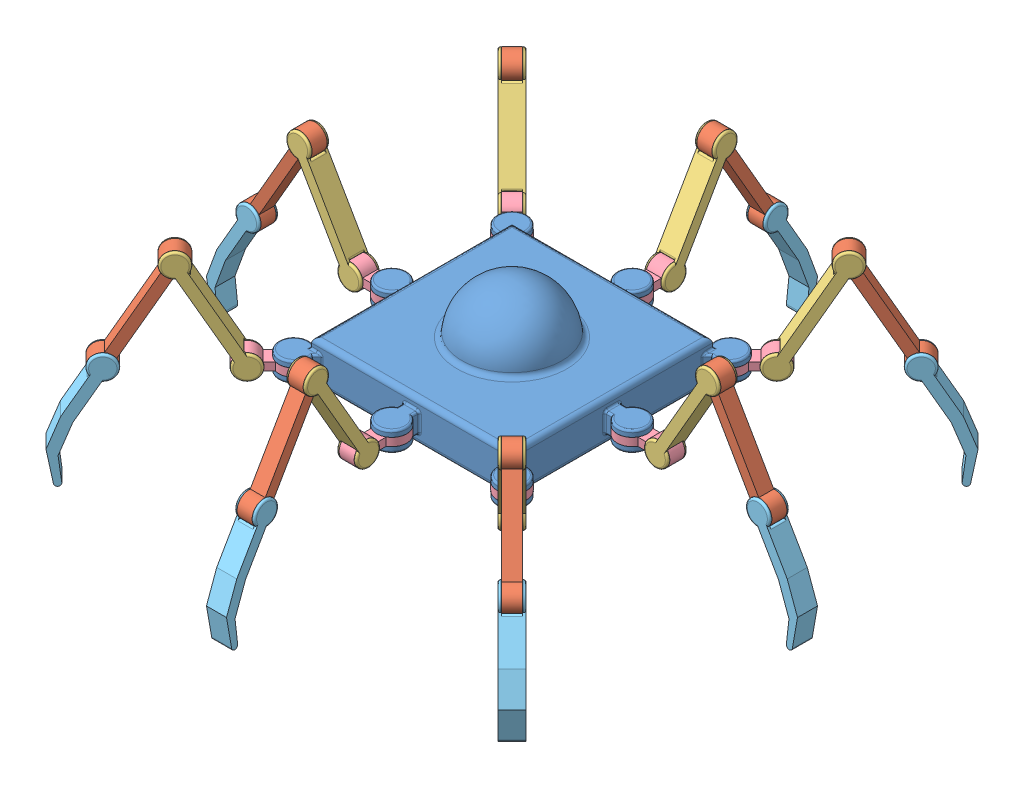
SolidWorks assembly SpiderBot_3Legs, configuration Default. Lengths in mm.
Overall size (634.89 234.57 634.89).
33 component instances, 5 part files, 146 mates.
Components (placement in the parent):
- spider_body-1: spider_body [Default] at (0 150 0) x (0 0 -1) z (0 -1 0) size (270 270 90)
- Link_C-24: Link_C [Default] at (-183.9152 176.5882 -194.5218) x (0.353553 0.866025 0.353553) z (-0.707107 0 0.707107) size (125.82 24 15)
- Link_B-24: Link_B [Default] at (-140.0258 176.5882 -154.1679) x (-0.707107 0 0.707107) z (-0.353553 0.866025 -0.353553) size (20.32 24 125.82)
- Link_A-24: Link_A [Default] at (-108.832 134 -108.832) x (-0.707107 0 -0.707107) z (0 -1 0) size (59.99 30 24)
- Link_D-24: Link_D [Default] at (-232.2874 88.4118 -218.1453) x (0.707107 0 -0.707107) z (0.353553 0.866025 0.353553) size (20.32 36.78 116.49)
- Link_C-26: Link_C [Default] at (-194.5218 176.5882 183.9152) x (0.353553 0.866025 -0.353553) z (0.707107 0 0.707107) size (125.82 24 15)
- Link_B-26: Link_B [Default] at (-154.1679 176.5882 140.0258) x (0.707107 0 0.707107) z (-0.353553 0.866025 0.353553) size (20.32 24 125.82)
- Link_A-26: Link_A [Default] at (-108.832 134 108.832) x (-0.707107 0 0.707107) z (0 -1 0) size (59.99 30 24)
- Link_D-26: Link_D [Default] at (-218.1453 88.4118 232.2874) x (-0.707107 0 -0.707107) z (0.353553 0.866025 -0.353553) size (20.32 36.78 116.49)
- Link_C-27: Link_C [Default] at (183.9152 176.5882 194.5218) x (-0.353553 0.866025 -0.353553) z (0.707107 0 -0.707107) size (125.82 24 15)
- Link_B-27: Link_B [Default] at (140.0258 176.5882 154.1679) x (0.707107 0 -0.707107) z (0.353553 0.866025 0.353553) size (20.32 24 125.82)
- Link_A-27: Link_A [Default] at (108.832 134 108.832) x (0.707107 0 0.707107) z (0 -1 0) size (59.99 30 24)
- Link_D-27: Link_D [Default] at (232.2874 88.4118 218.1453) x (-0.707107 0 0.707107) z (-0.353553 0.866025 -0.353553) size (20.32 36.78 116.49)
- Link_B-33: Link_B [Default] at (154.1679 176.5882 -140.0258) x (-0.707107 0 -0.707107) z (0.353553 0.866025 -0.353553) size (20.32 24 125.82)
- Link_D-31: Link_D [Default] at (218.1453 88.4118 -232.2874) x (0.707107 0 0.707107) z (-0.353553 0.866025 0.353553) size (20.32 36.78 116.49)
- Link_A-31: Link_A [Default] at (108.832 134 -108.832) x (0.707107 0 -0.707107) z (0 -1 0) size (59.99 30 24)
- Link_C-31: Link_C [Default] at (194.5218 176.5882 -183.9152) x (-0.353553 0.866025 0.353553) z (-0.707107 0 -0.707107) size (125.82 24 15)
- Link_D-34: Link_D [Default] at (-284.5923 88.4118 10) x (0 0 -1) z (0.5 0.866025 0) size (20.32 36.78 116.49)
- Link_A-34: Link_A [Default] at (-120 134 0) x (-1 0 0) z (0 -1 0) size (59.99 30 24)
- Link_B-36: Link_B [Default] at (-174.1146 176.5882 -10) x (0 0 1) z (-0.5 0.866025 0) size (20.32 24 125.82)
- Link_C-34: Link_C [Default] at (-233.6836 176.5882 -7.5) x (0.5 0.866025 0) z (0 0 1) size (125.82 24 15)
- Link_A-35: Link_A [Default] at (120 134 0) x (1 0 0) z (0 -1 0) size (59.99 30 24)
- Link_D-35: Link_D [Default] at (284.5923 88.4118 -10) x (0 0 1) z (-0.5 0.866025 0) size (20.32 36.78 116.49)
- Link_C-35: Link_C [Default] at (233.6836 176.5882 7.5) x (-0.5 0.866025 0) z (0 0 -1) size (125.82 24 15)
- Link_B-37: Link_B [Default] at (174.1146 176.5882 10) x (0 0 -1) z (0.5 0.866025 0) size (20.32 24 125.82)
- Link_A-36: Link_A [Default] at (0 134 120) x (0 0 1) z (0 -1 0) size (59.99 30 24)
- Link_D-36: Link_D [Default] at (10 88.4118 284.5923) x (-1 0 0) z (0 0.866025 -0.5) size (20.32 36.78 116.49)
- Link_C-36: Link_C [Default] at (-7.5 176.5882 233.6836) x (0 0.866025 -0.5) z (1 0 0) size (125.82 24 15)
- Link_B-38: Link_B [Default] at (-10 176.5882 174.1146) x (1 0 0) z (0 0.866025 0.5) size (20.32 24 125.82)
- Link_A-37: Link_A [Default] at (0 134 -120) x (0 0 -1) z (0 -1 0) size (59.99 30 24)
- Link_D-37: Link_D [Default] at (-10 88.4118 -284.5923) x (1 0 0) z (0 0.866025 0.5) size (20.32 36.78 116.49)
- Link_C-37: Link_C [Default] at (7.5 176.5882 -233.6836) x (0 0.866025 0.5) z (-1 0 0) size (125.82 24 15)
- Link_B-39: Link_B [Default] at (10 176.5882 -174.1146) x (-1 0 0) z (0 0.866025 -0.5) size (20.32 24 125.82)
Mates (geometry in assembly coordinates):
- Coincident4: coincident anti-aligned: plane of Link_B-2 through (235.0341 -365.5738 720.8033) normal (-1 0 0); plane of Link_C-2 through (235.0341 -453.7502 771.712) normal (1 0 0)
- Concentric4: concentric anti-aligned: cylinder of Link_B-2 through (220.0341 -365.5738 720.8033) axis (1 0 0) radius 4; cylinder of Link_C-2 through (235.0341 -365.5738 720.8033) axis (-1 0 0) radius 4
- Coincident5: coincident anti-aligned: plane of Link_C-2 through (235.0341 -453.7502 771.712) normal (1 0 0); plane of Link_D-2 through (235.0341 -453.7502 771.712) normal (-1 0 0)
- Concentric6: concentric aligned: cylinder of Link_C-2 through (235.0341 -453.7502 771.712) axis (-1 0 0) radius 4; cylinder of Link_D-2 through (235.0341 -453.7502 771.712) axis (-1 0 0) radius 4
- Coincident7: coincident anti-aligned: plane of Link_B-3 through (281.248 -759.0313 934.2797) normal (-1 0 0); plane of Link_C-3 through (281.248 -847.2078 985.1885) normal (1 0 0)
- Concentric7: concentric anti-aligned: cylinder of Link_B-3 through (266.248 -759.0313 934.2797) axis (1 0 0) radius 4; cylinder of Link_C-3 through (281.248 -759.0313 934.2797) axis (-1 0 0) radius 4
- Coincident8: coincident anti-aligned: plane of Link_C-3 through (281.248 -847.2078 985.1885) normal (1 0 0); plane of Link_D-3 through (281.248 -847.2078 985.1885) normal (-1 0 0)
- Concentric9: concentric aligned: cylinder of Link_C-3 through (281.248 -847.2078 985.1885) axis (-1 0 0) radius 4; cylinder of Link_D-3 through (281.248 -847.2078 985.1885) axis (-1 0 0) radius 4
- Coincident10: coincident anti-aligned: plane of Link_B-4 through (178.5336 -465.5708 822.703) normal (-1 0 0); plane of Link_C-4 through (178.5336 -553.7473 873.6117) normal (1 0 0)
- Concentric10: concentric anti-aligned: cylinder of Link_B-4 through (163.5336 -465.5708 822.703) axis (1 0 0) radius 4; cylinder of Link_C-4 through (178.5336 -465.5708 822.703) axis (-1 0 0) radius 4
- Coincident11: coincident anti-aligned: plane of Link_C-4 through (178.5336 -553.7473 873.6117) normal (1 0 0); plane of Link_D-4 through (178.5336 -553.7473 873.6117) normal (-1 0 0)
- Concentric12: concentric aligned: cylinder of Link_C-4 through (178.5336 -553.7473 873.6117) axis (-1 0 0) radius 4; cylinder of Link_D-4 through (178.5336 -553.7473 873.6117) axis (-1 0 0) radius 4
- Coincident13: coincident anti-aligned: plane of Link_B-5 through (262.376 -1013.0932 1106.1332) normal (-1 0 0); plane of Link_C-5 through (262.376 -1101.2696 1157.0419) normal (1 0 0)
- Concentric13: concentric anti-aligned: cylinder of Link_B-5 through (247.376 -1013.0932 1106.1332) axis (1 0 0) radius 4; cylinder of Link_C-5 through (262.376 -1013.0932 1106.1332) axis (-1 0 0) radius 4
- Coincident14: coincident anti-aligned: plane of Link_C-5 through (262.376 -1101.2696 1157.0419) normal (1 0 0); plane of Link_D-5 through (262.376 -1101.2696 1157.0419) normal (-1 0 0)
- Concentric15: concentric aligned: cylinder of Link_C-5 through (262.376 -1101.2696 1157.0419) axis (-1 0 0) radius 4; cylinder of Link_D-5 through (262.376 -1101.2696 1157.0419) axis (-1 0 0) radius 4
- Coincident16: coincident anti-aligned: plane of Link_B-6 through (534.9738 -1642.7072 1309.0583) normal (-1 0 0); plane of Link_C-6 through (534.9738 -1730.8837 1359.9671) normal (1 0 0)
- Concentric16: concentric anti-aligned: cylinder of Link_B-6 through (519.9738 -1642.7072 1309.0583) axis (1 0 0) radius 4; cylinder of Link_C-6 through (534.9738 -1642.7072 1309.0583) axis (-1 0 0) radius 4
- Coincident17: coincident anti-aligned: plane of Link_C-6 through (534.9738 -1730.8837 1359.9671) normal (1 0 0); plane of Link_D-6 through (534.9738 -1730.8837 1359.9671) normal (-1 0 0)
- Concentric18: concentric aligned: cylinder of Link_C-6 through (534.9738 -1730.8837 1359.9671) axis (-1 0 0) radius 4; cylinder of Link_D-6 through (534.9738 -1730.8837 1359.9671) axis (-1 0 0) radius 4
- Coincident19: coincident anti-aligned: plane of Link_B-7 through (-306.3909 -269.9837 1039.0888) normal (-1 0 0); plane of Link_C-7 through (-306.3909 -358.1602 1089.9975) normal (1 0 0)
- Concentric19: concentric anti-aligned: cylinder of Link_B-7 through (-321.3909 -269.9837 1039.0888) axis (1 0 0) radius 4; cylinder of Link_C-7 through (-306.3909 -269.9837 1039.0888) axis (-1 0 0) radius 4
- Coincident20: coincident anti-aligned: plane of Link_C-7 through (-306.3909 -358.1602 1089.9975) normal (1 0 0); plane of Link_D-7 through (-306.3909 -358.1602 1089.9975) normal (-1 0 0)
- Concentric21: concentric aligned: cylinder of Link_C-7 through (-306.3909 -358.1602 1089.9975) axis (-1 0 0) radius 4; cylinder of Link_D-7 through (-306.3909 -358.1602 1089.9975) axis (-1 0 0) radius 4
- Coincident22: coincident anti-aligned: plane of Link_B-8 through (-311.8852 -488.0983 1179.1514) normal (-1 0 0); plane of Link_C-8 through (-311.8852 -576.2747 1230.0601) normal (1 0 0)
- Concentric22: concentric anti-aligned: cylinder of Link_B-8 through (-326.8852 -488.0983 1179.1514) axis (1 0 0) radius 4; cylinder of Link_C-8 through (-311.8852 -488.0983 1179.1514) axis (-1 0 0) radius 4
- Coincident23: coincident anti-aligned: plane of Link_C-8 through (-311.8852 -576.2747 1230.0601) normal (1 0 0); plane of Link_D-8 through (-311.8852 -576.2747 1230.0601) normal (-1 0 0)
- Concentric24: concentric aligned: cylinder of Link_C-8 through (-311.8852 -576.2747 1230.0601) axis (-1 0 0) radius 4; cylinder of Link_D-8 through (-311.8852 -576.2747 1230.0601) axis (-1 0 0) radius 4
- Coincident25: coincident anti-aligned: plane of Link_B-9 through (-611.4857 -390.9688 1327.6493) normal (-1 0 0); plane of Link_C-9 through (-611.4857 -479.1453 1378.558) normal (1 0 0)
- Concentric25: concentric anti-aligned: cylinder of Link_B-9 through (-626.4857 -390.9688 1327.6493) axis (1 0 0) radius 4; cylinder of Link_C-9 through (-611.4857 -390.9688 1327.6493) axis (-1 0 0) radius 4
- Coincident26: coincident anti-aligned: plane of Link_C-9 through (-611.4857 -479.1453 1378.558) normal (1 0 0); plane of Link_D-9 through (-611.4857 -479.1453 1378.558) normal (-1 0 0)
- Concentric27: concentric aligned: cylinder of Link_C-9 through (-611.4857 -479.1453 1378.558) axis (-1 0 0) radius 4; cylinder of Link_D-9 through (-611.4857 -479.1453 1378.558) axis (-1 0 0) radius 4
- Coincident28: coincident anti-aligned: plane of Link_B-10 through (-139.42 -657.5126 1164.5577) normal (-1 0 0); plane of Link_C-10 through (-139.42 -745.689 1215.4664) normal (1 0 0)
- Concentric28: concentric anti-aligned: cylinder of Link_B-10 through (-154.42 -657.5126 1164.5577) axis (1 0 0) radius 4; cylinder of Link_C-10 through (-139.42 -657.5126 1164.5577) axis (-1 0 0) radius 4
- Coincident29: coincident anti-aligned: plane of Link_C-10 through (-139.42 -745.689 1215.4664) normal (1 0 0); plane of Link_D-10 through (-139.42 -745.689 1215.4664) normal (-1 0 0)
- Concentric30: concentric aligned: cylinder of Link_C-10 through (-139.42 -745.689 1215.4664) axis (-1 0 0) radius 4; cylinder of Link_D-10 through (-139.42 -745.689 1215.4664) axis (-1 0 0) radius 4
- Coincident31: coincident anti-aligned: plane of Link_B-11 through (-139.42 -657.5126 1164.5577) normal (-1 0 0); plane of Link_C-11 through (-139.42 -745.689 1215.4664) normal (1 0 0)
- Concentric31: concentric anti-aligned: cylinder of Link_B-11 through (-154.42 -657.5126 1164.5577) axis (1 0 0) radius 4; cylinder of Link_C-11 through (-139.42 -657.5126 1164.5577) axis (-1 0 0) radius 4
- Coincident32: coincident anti-aligned: plane of Link_C-11 through (-139.42 -745.689 1215.4664) normal (1 0 0); plane of Link_D-11 through (-139.42 -745.689 1215.4664) normal (-1 0 0)
- Concentric33: concentric aligned: cylinder of Link_C-11 through (-139.42 -745.689 1215.4664) axis (-1 0 0) radius 4; cylinder of Link_D-11 through (-139.42 -745.689 1215.4664) axis (-1 0 0) radius 4
- Coincident34: coincident anti-aligned: plane of Link_B-12 through (-94.7509 -804.43 1225.1322) normal (-1 0 0); plane of Link_C-12 through (-94.7509 -892.6065 1276.0409) normal (1 0 0)
- Concentric34: concentric anti-aligned: cylinder of Link_B-12 through (-109.7509 -804.43 1225.1322) axis (1 0 0) radius 4; cylinder of Link_C-12 through (-94.7509 -804.43 1225.1322) axis (-1 0 0) radius 4
- Coincident35: coincident anti-aligned: plane of Link_C-12 through (-94.7509 -892.6065 1276.0409) normal (1 0 0); plane of Link_D-12 through (-94.7509 -892.6065 1276.0409) normal (-1 0 0)
- Concentric36: concentric aligned: cylinder of Link_C-12 through (-94.7509 -892.6065 1276.0409) axis (-1 0 0) radius 4; cylinder of Link_D-12 through (-94.7509 -892.6065 1276.0409) axis (-1 0 0) radius 4
- Concentric78: concentric anti-aligned: cylinder of Link_C-24 through (-173.461 218.1765 -162.8544) axis (0.707107 0 -0.707107) radius 4; cylinder of Link_B-24 through (-162.8544 218.1765 -173.461) axis (-0.707107 0 0.707107) radius 4
- Concentric79: concentric anti-aligned: cylinder of Link_B-24 through (-126.8565 130 -137.4631) axis (-0.707107 0 0.707107) radius 4; cylinder of Link_A-24 through (-142.7664 130 -121.5532) axis (0.707107 0 -0.707107) radius 5
- Coincident86: coincident anti-aligned: plane of Link_B-24 through (-137.4631 130 -126.8565) normal (0.707107 0 -0.707107); plane of Link_A-24 through (-123.3209 126 -112.7143) normal (-0.707107 0 0.707107)
- Coincident87: coincident anti-aligned: plane of Link_C-24 through (-198.8522 130 -209.4588) normal (0.707107 0 -0.707107); plane of Link_B-24 through (-162.8544 218.1765 -173.461) normal (-0.707107 0 0.707107)
- Coincident88: coincident anti-aligned: plane of Link_C-24 through (-209.4588 130 -198.8522) normal (-0.707107 0 0.707107); plane of Link_B-24 through (-173.461 218.1765 -162.8544) normal (0.707107 0 -0.707107)
- Coincident89: coincident anti-aligned: plane of Link_C-24 through (-198.8522 130 -209.4588) normal (0.707107 0 -0.707107); plane of Link_D-24 through (-198.8522 130 -209.4588) normal (-0.707107 0 0.707107)
- Concentric80: concentric aligned: cylinder of Link_C-24 through (-209.4588 130 -198.8522) axis (0.707107 0 -0.707107) radius 4; cylinder of Link_D-24 through (-209.4588 130 -198.8522) axis (0.707107 0 -0.707107) radius 4
- Coincident90: coincident anti-aligned: plane of Link_B-24 through (-126.8565 130 -137.4631) normal (-0.707107 0 0.707107); plane of Link_A-24 through (-112.7143 126 -123.3209) normal (0.707107 0 -0.707107)
- Coincident91: coincident anti-aligned: plane of Link_C-24 through (-209.4588 130 -198.8522) normal (-0.707107 0 0.707107); plane of Link_D-24 through (-209.4588 130 -198.8522) normal (0.707107 0 -0.707107)
- Concentric84: concentric anti-aligned: cylinder of Link_C-26 through (-162.8544 218.1765 173.461) axis (-0.707107 0 -0.707107) radius 4; cylinder of Link_B-26 through (-173.461 218.1765 162.8544) axis (0.707107 0 0.707107) radius 4
- Concentric85: concentric anti-aligned: cylinder of Link_B-26 through (-137.4631 130 126.8565) axis (0.707107 0 0.707107) radius 4; cylinder of Link_A-26 through (-121.5532 130 142.7664) axis (-0.707107 0 -0.707107) radius 5
- Coincident98: coincident anti-aligned: plane of Link_B-26 through (-126.8565 130 137.4631) normal (-0.707107 0 -0.707107); plane of Link_A-26 through (-112.7143 126 123.3209) normal (0.707107 0 0.707107)
- Coincident99: coincident anti-aligned: plane of Link_C-26 through (-209.4588 130 198.8522) normal (-0.707107 0 -0.707107); plane of Link_B-26 through (-173.461 218.1765 162.8544) normal (0.707107 0 0.707107)
- Coincident100: coincident anti-aligned: plane of Link_C-26 through (-198.8522 130 209.4588) normal (0.707107 0 0.707107); plane of Link_B-26 through (-162.8544 218.1765 173.461) normal (-0.707107 0 -0.707107)
- Coincident101: coincident anti-aligned: plane of Link_C-26 through (-209.4588 130 198.8522) normal (-0.707107 0 -0.707107); plane of Link_D-26 through (-209.4588 130 198.8522) normal (0.707107 0 0.707107)
- Concentric86: concentric aligned: cylinder of Link_C-26 through (-198.8522 130 209.4588) axis (-0.707107 0 -0.707107) radius 4; cylinder of Link_D-26 through (-198.8522 130 209.4588) axis (-0.707107 0 -0.707107) radius 4
- Coincident102: coincident anti-aligned: plane of Link_B-26 through (-137.4631 130 126.8565) normal (0.707107 0 0.707107); plane of Link_A-26 through (-123.3209 126 112.7143) normal (-0.707107 0 -0.707107)
- Coincident103: coincident anti-aligned: plane of Link_C-26 through (-198.8522 130 209.4588) normal (0.707107 0 0.707107); plane of Link_D-26 through (-198.8522 130 209.4588) normal (-0.707107 0 -0.707107)
- Concentric87: concentric anti-aligned: cylinder of Link_C-27 through (173.461 218.1765 162.8544) axis (-0.707107 0 0.707107) radius 4; cylinder of Link_B-27 through (162.8544 218.1765 173.461) axis (0.707107 0 -0.707107) radius 4
- Concentric88: concentric anti-aligned: cylinder of Link_B-27 through (126.8565 130 137.4631) axis (0.707107 0 -0.707107) radius 4; cylinder of Link_A-27 through (142.7664 130 121.5532) axis (-0.707107 0 0.707107) radius 5
- Coincident104: coincident anti-aligned: plane of Link_B-27 through (137.4631 130 126.8565) normal (-0.707107 0 0.707107); plane of Link_A-27 through (123.3209 126 112.7143) normal (0.707107 0 -0.707107)
- Coincident105: coincident anti-aligned: plane of Link_C-27 through (198.8522 130 209.4588) normal (-0.707107 0 0.707107); plane of Link_B-27 through (162.8544 218.1765 173.461) normal (0.707107 0 -0.707107)
- Coincident106: coincident anti-aligned: plane of Link_C-27 through (209.4588 130 198.8522) normal (0.707107 0 -0.707107); plane of Link_B-27 through (173.461 218.1765 162.8544) normal (-0.707107 0 0.707107)
- Coincident107: coincident anti-aligned: plane of Link_C-27 through (198.8522 130 209.4588) normal (-0.707107 0 0.707107); plane of Link_D-27 through (198.8522 130 209.4588) normal (0.707107 0 -0.707107)
- Concentric89: concentric aligned: cylinder of Link_C-27 through (209.4588 130 198.8522) axis (-0.707107 0 0.707107) radius 4; cylinder of Link_D-27 through (209.4588 130 198.8522) axis (-0.707107 0 0.707107) radius 4
- Coincident108: coincident anti-aligned: plane of Link_B-27 through (126.8565 130 137.4631) normal (0.707107 0 -0.707107); plane of Link_A-27 through (112.7143 126 123.3209) normal (-0.707107 0 0.707107)
- Coincident109: coincident anti-aligned: plane of Link_C-27 through (209.4588 130 198.8522) normal (0.707107 0 -0.707107); plane of Link_D-27 through (209.4588 130 198.8522) normal (-0.707107 0 0.707107)
- Coincident124: coincident anti-aligned: plane of spider_body-1 through (108.832 134 108.832) normal (0 -1 0); plane of Link_A-27 through (108.832 134 108.832) normal (0 1 0)
- Coincident125: coincident anti-aligned: plane of spider_body-1 through (108.832 126 108.832) normal (0 1 0); plane of Link_A-27 through (108.832 126 108.832) normal (0 -1 0)
- Concentric97: concentric anti-aligned: cylinder of spider_body-1 through (108.832 134 108.832) axis (0 -1 0) radius 10; cylinder of Link_A-27 through (108.832 126 108.832) axis (0 1 0) radius 10
- Coincident126: coincident anti-aligned: plane of spider_body-1 through (-108.832 134 108.832) normal (0 -1 0); plane of Link_A-26 through (-108.832 134 108.832) normal (0 1 0)
- Coincident127: coincident anti-aligned: plane of spider_body-1 through (-108.832 126 108.832) normal (0 1 0); plane of Link_A-26 through (-108.832 126 108.832) normal (0 -1 0)
- Concentric98: concentric anti-aligned: cylinder of spider_body-1 through (-108.832 134 108.832) axis (0 -1 0) radius 10; cylinder of Link_A-26 through (-108.832 126 108.832) axis (0 1 0) radius 10
- Coincident138: coincident anti-aligned: plane of Link_B-33 through (162.8544 218.1765 -173.461) normal (0.707107 0 0.707107); plane of Link_C-31 through (198.8522 130 -209.4588) normal (-0.707107 0 -0.707107)
- Coincident139: coincident anti-aligned: plane of Link_D-31 through (209.4588 130 -198.8522) normal (-0.707107 0 -0.707107); plane of Link_C-31 through (209.4588 130 -198.8522) normal (0.707107 0 0.707107)
- Coincident140: coincident anti-aligned: plane of Link_D-31 through (198.8522 130 -209.4588) normal (0.707107 0 0.707107); plane of Link_C-31 through (198.8522 130 -209.4588) normal (-0.707107 0 -0.707107)
- Concentric104: concentric aligned: cylinder of Link_D-31 through (198.8522 130 -209.4588) axis (0.707107 0 0.707107) radius 4; cylinder of Link_C-31 through (198.8522 130 -209.4588) axis (0.707107 0 0.707107) radius 4
- Coincident141: coincident anti-aligned: plane of Link_B-33 through (137.4631 130 -126.8565) normal (-0.707107 0 -0.707107); plane of Link_A-31 through (123.3209 126 -112.7143) normal (0.707107 0 0.707107)
- Concentric105: concentric anti-aligned: cylinder of Link_B-33 through (173.461 218.1765 -162.8544) axis (-0.707107 0 -0.707107) radius 4; cylinder of Link_C-31 through (162.8544 218.1765 -173.461) axis (0.707107 0 0.707107) radius 4
- Concentric106: concentric anti-aligned: cylinder of Link_B-33 through (137.4631 130 -126.8565) axis (-0.707107 0 -0.707107) radius 4; cylinder of Link_A-31 through (121.5532 130 -142.7664) axis (0.707107 0 0.707107) radius 5
- Coincident142: coincident anti-aligned: plane of Link_B-33 through (126.8565 130 -137.4631) normal (0.707107 0 0.707107); plane of Link_A-31 through (112.7143 126 -123.3209) normal (-0.707107 0 -0.707107)
- Coincident143: coincident anti-aligned: plane of Link_B-33 through (173.461 218.1765 -162.8544) normal (-0.707107 0 -0.707107); plane of Link_C-31 through (209.4588 130 -198.8522) normal (0.707107 0 0.707107)
- Coincident146: coincident anti-aligned: plane of spider_body-1 through (108.832 134 -108.832) normal (0 -1 0); plane of Link_A-31 through (108.832 134 -108.832) normal (0 1 0)
- Coincident147: coincident anti-aligned: plane of spider_body-1 through (108.832 126 -108.832) normal (0 1 0); plane of Link_A-31 through (108.832 126 -108.832) normal (0 -1 0)
- Concentric108: concentric anti-aligned: cylinder of spider_body-1 through (108.832 134 -108.832) axis (0 -1 0) radius 10; cylinder of Link_A-31 through (108.832 126 -108.832) axis (0 1 0) radius 10
- Coincident148: coincident anti-aligned: plane of spider_body-1 through (-108.832 134 -108.832) normal (0 -1 0); plane of Link_A-24 through (-108.832 134 -108.832) normal (0 1 0)
- Coincident149: coincident anti-aligned: plane of spider_body-1 through (-108.832 126 -108.832) normal (0 1 0); plane of Link_A-24 through (-108.832 126 -108.832) normal (0 -1 0)
- Concentric109: concentric anti-aligned: cylinder of spider_body-1 through (-108.832 134 -108.832) axis (0 -1 0) radius 10; cylinder of Link_A-24 through (-108.832 126 -108.832) axis (0 1 0) radius 10
- Concentric111: concentric anti-aligned: cylinder of Link_A-32 through (-1752.5654 2022.5976 -1745.769) axis (0.707107 0 -0.707107) radius 5; cylinder of Link_B-34 through (-1736.6555 2022.5976 -1761.6789) axis (-0.707107 0 0.707107) radius 4
- Coincident151: coincident anti-aligned: plane of Link_B-34 through (-1783.26 2110.774 -1787.0702) normal (0.707107 0 -0.707107); plane of Link_C-32 through (-1819.2579 2022.5976 -1823.0681) normal (-0.707107 0 0.707107)
- Concentric112: concentric anti-aligned: cylinder of Link_B-34 through (-1772.6534 2110.774 -1797.6768) axis (-0.707107 0 0.707107) radius 4; cylinder of Link_C-32 through (-1783.26 2110.774 -1787.0702) axis (0.707107 0 -0.707107) radius 4
- Coincident153: coincident anti-aligned: plane of Link_A-32 through (-1733.12 2018.5976 -1736.9302) normal (-0.707107 0 0.707107); plane of Link_B-34 through (-1747.2621 2022.5976 -1751.0723) normal (0.707107 0 -0.707107)
- Coincident154: coincident anti-aligned: plane of Link_B-34 through (-1772.6534 2110.774 -1797.6768) normal (-0.707107 0 0.707107); plane of Link_C-32 through (-1808.6513 2022.5976 -1833.6747) normal (0.707107 0 -0.707107)
- Coincident155: coincident anti-aligned: plane of Link_A-32 through (-1722.5134 2018.5976 -1747.5368) normal (0.707107 0 -0.707107); plane of Link_B-34 through (-1736.6555 2022.5976 -1761.6789) normal (-0.707107 0 0.707107)
- Concentric116: concentric aligned: cylinder of Link_D-34 through (-254.8078 130 7.5) axis (0 0 -1) radius 4; cylinder of Link_C-34 through (-254.8078 130 7.5) axis (0 0 -1) radius 4
- Coincident162: coincident anti-aligned: plane of Link_D-34 through (-254.8078 130 7.5) normal (0 0 -1); plane of Link_C-34 through (-254.8078 130 7.5) normal (0 0 1)
- Concentric117: concentric anti-aligned: cylinder of Link_A-34 through (-152.9904 130 15) axis (0 0 -1) radius 5; cylinder of Link_B-36 through (-152.9904 130 -7.5) axis (0 0 1) radius 4
- Coincident163: coincident anti-aligned: plane of Link_B-36 through (-203.8991 218.1765 7.5) normal (0 0 -1); plane of Link_C-34 through (-254.8078 130 7.5) normal (0 0 1)
- Concentric118: concentric anti-aligned: cylinder of Link_B-36 through (-203.8991 218.1765 -7.5) axis (0 0 1) radius 4; cylinder of Link_C-34 through (-203.8991 218.1765 7.5) axis (0 0 -1) radius 4
- Coincident164: coincident anti-aligned: plane of Link_D-34 through (-254.8078 130 -7.5) normal (0 0 1); plane of Link_C-34 through (-254.8078 130 -7.5) normal (0 0 -1)
- Coincident165: coincident anti-aligned: plane of Link_A-34 through (-132.9904 126 7.5) normal (0 0 1); plane of Link_B-36 through (-152.9904 130 7.5) normal (0 0 -1)
- Coincident166: coincident anti-aligned: plane of Link_B-36 through (-203.8991 218.1765 -7.5) normal (0 0 1); plane of Link_C-34 through (-254.8078 130 -7.5) normal (0 0 -1)
- Coincident167: coincident anti-aligned: plane of Link_A-34 through (-132.9904 126 -7.5) normal (0 0 -1); plane of Link_B-36 through (-152.9904 130 -7.5) normal (0 0 1)
- Concentric119: concentric aligned: cylinder of Link_D-35 through (254.8078 130 -7.5) axis (0 0 1) radius 4; cylinder of Link_C-35 through (254.8078 130 -7.5) axis (0 0 1) radius 4
- Concentric120: concentric anti-aligned: cylinder of Link_C-35 through (203.8991 218.1765 -7.5) axis (0 0 1) radius 4; cylinder of Link_B-37 through (203.8991 218.1765 7.5) axis (0 0 -1) radius 4
- Coincident168: coincident anti-aligned: plane of Link_A-35 through (132.9904 126 7.5) normal (0 0 1); plane of Link_B-37 through (152.9904 130 7.5) normal (0 0 -1)
- Coincident169: coincident anti-aligned: plane of Link_A-35 through (132.9904 126 -7.5) normal (0 0 -1); plane of Link_B-37 through (152.9904 130 -7.5) normal (0 0 1)
- Coincident170: coincident anti-aligned: plane of Link_D-35 through (254.8078 130 -7.5) normal (0 0 1); plane of Link_C-35 through (254.8078 130 -7.5) normal (0 0 -1)
- Concentric121: concentric anti-aligned: cylinder of Link_A-35 through (152.9904 130 -15) axis (0 0 1) radius 5; cylinder of Link_B-37 through (152.9904 130 7.5) axis (0 0 -1) radius 4
- Coincident171: coincident anti-aligned: plane of Link_C-35 through (254.8078 130 -7.5) normal (0 0 -1); plane of Link_B-37 through (203.8991 218.1765 -7.5) normal (0 0 1)
- Coincident172: coincident anti-aligned: plane of Link_D-35 through (254.8078 130 7.5) normal (0 0 -1); plane of Link_C-35 through (254.8078 130 7.5) normal (0 0 1)
- Coincident173: coincident anti-aligned: plane of Link_C-35 through (254.8078 130 7.5) normal (0 0 1); plane of Link_B-37 through (203.8991 218.1765 7.5) normal (0 0 -1)
- Concentric122: concentric aligned: cylinder of Link_D-36 through (7.5 130 254.8078) axis (-1 0 0) radius 4; cylinder of Link_C-36 through (7.5 130 254.8078) axis (-1 0 0) radius 4
- Concentric123: concentric anti-aligned: cylinder of Link_C-36 through (7.5 218.1765 203.8991) axis (-1 0 0) radius 4; cylinder of Link_B-38 through (-7.5 218.1765 203.8991) axis (1 0 0) radius 4
- Coincident174: coincident anti-aligned: plane of Link_A-36 through (-7.5 126 132.9904) normal (-1 0 0); plane of Link_B-38 through (-7.5 130 152.9904) normal (1 0 0)
- Coincident175: coincident anti-aligned: plane of Link_A-36 through (7.5 126 132.9904) normal (1 0 0); plane of Link_B-38 through (7.5 130 152.9904) normal (-1 0 0)
- Coincident176: coincident anti-aligned: plane of Link_D-36 through (7.5 130 254.8078) normal (-1 0 0); plane of Link_C-36 through (7.5 130 254.8078) normal (1 0 0)
- Concentric124: concentric anti-aligned: cylinder of Link_A-36 through (15 130 152.9904) axis (-1 0 0) radius 5; cylinder of Link_B-38 through (-7.5 130 152.9904) axis (1 0 0) radius 4
- Coincident177: coincident anti-aligned: plane of Link_C-36 through (7.5 130 254.8078) normal (1 0 0); plane of Link_B-38 through (7.5 218.1765 203.8991) normal (-1 0 0)
- Coincident178: coincident anti-aligned: plane of Link_D-36 through (-7.5 130 254.8078) normal (1 0 0); plane of Link_C-36 through (-7.5 130 254.8078) normal (-1 0 0)
- Coincident179: coincident anti-aligned: plane of Link_C-36 through (-7.5 130 254.8078) normal (-1 0 0); plane of Link_B-38 through (-7.5 218.1765 203.8991) normal (1 0 0)
- Concentric125: concentric aligned: cylinder of Link_D-37 through (-7.5 130 -254.8078) axis (1 0 0) radius 4; cylinder of Link_C-37 through (-7.5 130 -254.8078) axis (1 0 0) radius 4
- Concentric126: concentric anti-aligned: cylinder of Link_C-37 through (-7.5 218.1765 -203.8991) axis (1 0 0) radius 4; cylinder of Link_B-39 through (7.5 218.1765 -203.8991) axis (-1 0 0) radius 4
- Coincident180: coincident anti-aligned: plane of Link_A-37 through (7.5 126 -132.9904) normal (1 0 0); plane of Link_B-39 through (7.5 130 -152.9904) normal (-1 0 0)
- Coincident181: coincident anti-aligned: plane of Link_A-37 through (-7.5 126 -132.9904) normal (-1 0 0); plane of Link_B-39 through (-7.5 130 -152.9904) normal (1 0 0)
- Coincident182: coincident anti-aligned: plane of Link_D-37 through (-7.5 130 -254.8078) normal (1 0 0); plane of Link_C-37 through (-7.5 130 -254.8078) normal (-1 0 0)
- Concentric127: concentric anti-aligned: cylinder of Link_A-37 through (-15 130 -152.9904) axis (1 0 0) radius 5; cylinder of Link_B-39 through (7.5 130 -152.9904) axis (-1 0 0) radius 4
- Coincident183: coincident anti-aligned: plane of Link_C-37 through (-7.5 130 -254.8078) normal (-1 0 0); plane of Link_B-39 through (-7.5 218.1765 -203.8991) normal (1 0 0)
- Coincident184: coincident anti-aligned: plane of Link_D-37 through (7.5 130 -254.8078) normal (-1 0 0); plane of Link_C-37 through (7.5 130 -254.8078) normal (1 0 0)
- Coincident185: coincident anti-aligned: plane of Link_C-37 through (7.5 130 -254.8078) normal (1 0 0); plane of Link_B-39 through (7.5 218.1765 -203.8991) normal (-1 0 0)
- Coincident187: coincident anti-aligned: plane of spider_body-1 through (-120 134 0) normal (0 -1 0); plane of Link_A-34 through (-120 134 0) normal (0 1 0)
- Coincident188: coincident anti-aligned: plane of spider_body-1 through (-120 126 0) normal (0 1 0); plane of Link_A-34 through (-120 126 0) normal (0 -1 0)
- Concentric129: concentric anti-aligned: cylinder of spider_body-1 through (-120 134 0) axis (0 -1 0) radius 10; cylinder of Link_A-34 through (-120 126 0) axis (0 1 0) radius 10
- Coincident189: coincident anti-aligned: plane of spider_body-1 through (0 134 -120) normal (0 -1 0); plane of Link_A-37 through (0 134 -120) normal (0 1 0)
- Coincident190: coincident anti-aligned: plane of spider_body-1 through (0 126 -120) normal (0 1 0); plane of Link_A-37 through (0 126 -120) normal (0 -1 0)
- Concentric130: concentric anti-aligned: cylinder of spider_body-1 through (0 134 -120) axis (0 -1 0) radius 10; cylinder of Link_A-37 through (0 126 -120) axis (0 1 0) radius 10
- Coincident191: coincident anti-aligned: plane of spider_body-1 through (120 134 0) normal (0 -1 0); plane of Link_A-35 through (120 134 0) normal (0 1 0)
- Coincident192: coincident anti-aligned: plane of spider_body-1 through (120 126 0) normal (0 1 0); plane of Link_A-35 through (120 126 0) normal (0 -1 0)
- Concentric131: concentric anti-aligned: cylinder of spider_body-1 through (120 134 0) axis (0 -1 0) radius 10; cylinder of Link_A-35 through (120 126 0) axis (0 1 0) radius 10
- Coincident193: coincident anti-aligned: plane of spider_body-1 through (0 134 120) normal (0 -1 0); plane of Link_A-36 through (0 134 120) normal (0 1 0)
- Coincident194: coincident anti-aligned: plane of spider_body-1 through (0 126 120) normal (0 1 0); plane of Link_A-36 through (0 126 120) normal (0 -1 0)
- Concentric132: concentric anti-aligned: cylinder of spider_body-1 through (0 134 120) axis (0 -1 0) radius 10; cylinder of Link_A-36 through (0 126 120) axis (0 1 0) radius 10
